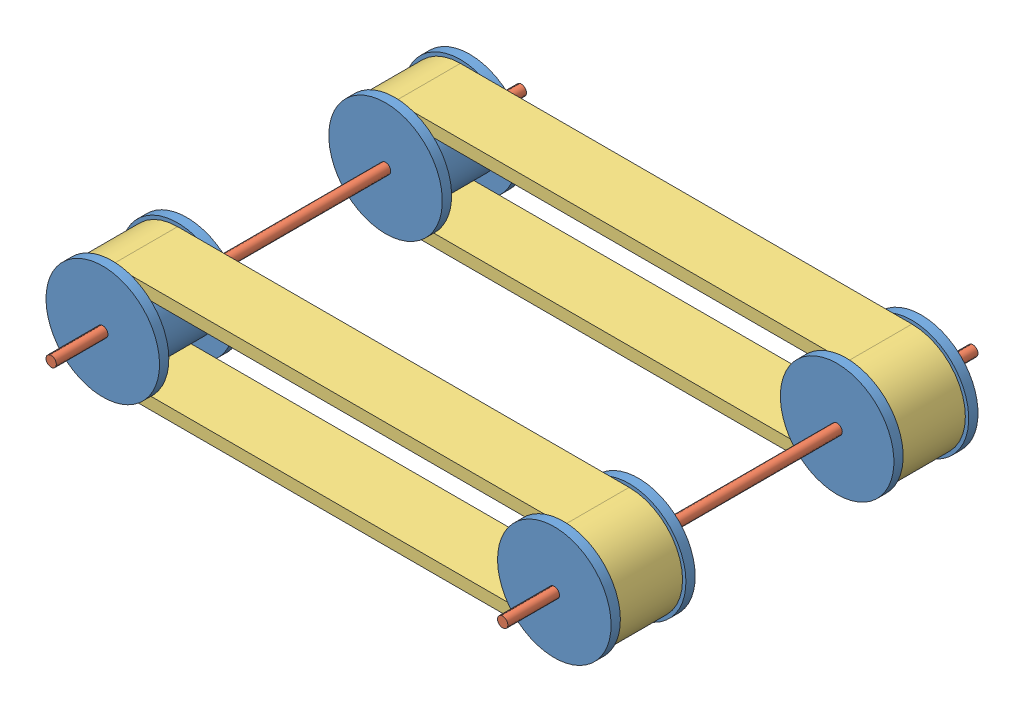
SolidWorks assembly Wheel Assembly, configuration Default. Lengths in mm.
Overall size (227.01 52.01 182.2).
8 component instances, 3 part files, 16 mates.
Components (placement in the parent):
- Wheel-1: Wheel [Default] at (-179.6884 129.9573 255.9581) x (0 0 -1) z (0.97923 0.202752 0) size (32.6 44 44)
- Wheel-2: Wheel [Default] at (-179.6884 129.9573 146.3581) x (0 0 -1) z (1 0 0) size (32.6 44 44)
- Wheel Axle-4: Wheel Axle [Default] at (-179.6884 129.9573 126.3581) size (2.5 2.5 182.2)
- Treads-1: Treads [Default] at (-92.1884 129.9573 259.5581) size (216.4 41.4 25.4)
- Treads-2: Treads [Default] at (-92.1884 129.9573 149.9581) size (216.4 41.4 25.4)
- Wheel Axle-5: Wheel Axle [Default] at (-4.6884 129.9573 126.3581) size (2.5 2.5 182.2)
- Wheel-3: Wheel [Default] at (-4.6884 129.9573 146.3581) x (0 0 -1) z (1 0 0) size (32.6 44 44)
- Wheel-4: Wheel [Default] at (-4.6884 129.9573 255.9581) x (0 0 -1) z (0.97923 0.202752 0) size (32.6 44 44)
Mates (geometry in assembly coordinates):
- Concentric15: concentric aligned: cylinder of Wheel-1 through (-179.6884 129.9573 255.9581) axis (0 0 1) radius 1.25; cylinder of Wheel-2 through (-179.6884 129.9573 146.3581) axis (0 0 1) radius 1.25
- Concentric16: concentric anti-aligned: cylinder of Wheel-1 through (-179.6884 129.9573 255.9581) axis (0 0 1) radius 1.25; cylinder of Wheel Axle-4 through (-179.6884 129.9573 308.5581) axis (0 0 -1) radius 1.25
- Concentric17: concentric aligned: cylinder of Wheel-3 through (-4.6884 129.9573 146.3581) axis (0 0 1) radius 1.25; cylinder of Wheel-4 through (-4.6884 129.9573 255.9581) axis (0 0 1) radius 1.25
- Concentric18: concentric anti-aligned: cylinder of Wheel Axle-5 through (-4.6884 129.9573 308.5581) axis (0 0 -1) radius 1.25; cylinder of Wheel-4 through (-4.6884 129.9573 255.9581) axis (0 0 1) radius 1.25
- Concentric19: concentric aligned: cylinder of Treads-1 through (-4.6884 129.9573 284.9581) axis (0 0 -1) radius 20.7; cylinder of Wheel-4 through (-4.6884 129.9573 255.9581) axis (0 0 -1) radius 15
- Concentric20: concentric aligned: cylinder of Treads-2 through (-4.6884 129.9573 175.3581) axis (0 0 -1) radius 20.7; cylinder of Wheel-3 through (-4.6884 129.9573 146.3581) axis (0 0 -1) radius 15
- Concentric21: concentric aligned: cylinder of Wheel-1 through (-179.6884 129.9573 255.9581) axis (0 0 -1) radius 15; cylinder of Treads-1 through (-179.6884 129.9573 284.9581) axis (0 0 -1) radius 16
- Concentric22: concentric aligned: cylinder of Wheel-2 through (-179.6884 129.9573 146.3581) axis (0 0 -1) radius 15; cylinder of Treads-2 through (-179.6884 129.9573 175.3581) axis (0 0 -1) radius 20.7
- Coincident1: coincident anti-aligned: plane of Treads-1 through (-4.6884 129.9573 284.9581) normal (0 0 1); plane of Wheel-4 through (-4.6884 129.9573 284.9581) normal (0 0 -1)
- Coincident2: coincident anti-aligned: plane of Wheel-2 through (-179.6884 129.9573 149.9581) normal (0 0 1); plane of Treads-2 through (-4.6884 129.9573 149.9581) normal (0 0 -1)
- Coincident3: coincident anti-aligned: plane of Wheel-1 through (-179.6884 129.9573 284.9581) normal (0 0 -1); plane of Treads-1 through (-4.6884 129.9573 284.9581) normal (0 0 1)
- Distance9: distance = 142.2 mm anti-aligned: plane of Wheel-4 through (-4.6884 129.9573 288.5581) normal (0 0 1); plane of Wheel-3 through (-4.6884 129.9573 146.3581) normal (0 0 -1)
- Distance10: distance = 20 mm aligned: plane of Wheel-4 through (-4.6884 129.9573 288.5581) normal (0 0 1); plane of Wheel Axle-5 through (-4.6884 129.9573 308.5581) normal (0 0 1)
- Parallel1: parallel aligned: plane of Wheel Axle-4 through (-179.6884 129.9573 308.5581) normal (0 0 1); plane of Wheel Axle-5 through (-4.6884 129.9573 308.5581) normal (0 0 1)
- Coincident11: coincident anti-aligned: plane of Treads-2 through (-4.6884 129.9573 149.9581) normal (0 0 -1); plane of Wheel-3 through (-4.6884 129.9573 149.9581) normal (0 0 1)
- Coincident13: coincident aligned: plane of Wheel Axle-4 through (-179.6884 129.9573 126.3581) normal (0 0 -1); plane of Wheel Axle-5 through (-4.6884 129.9573 126.3581) normal (0 0 -1)
